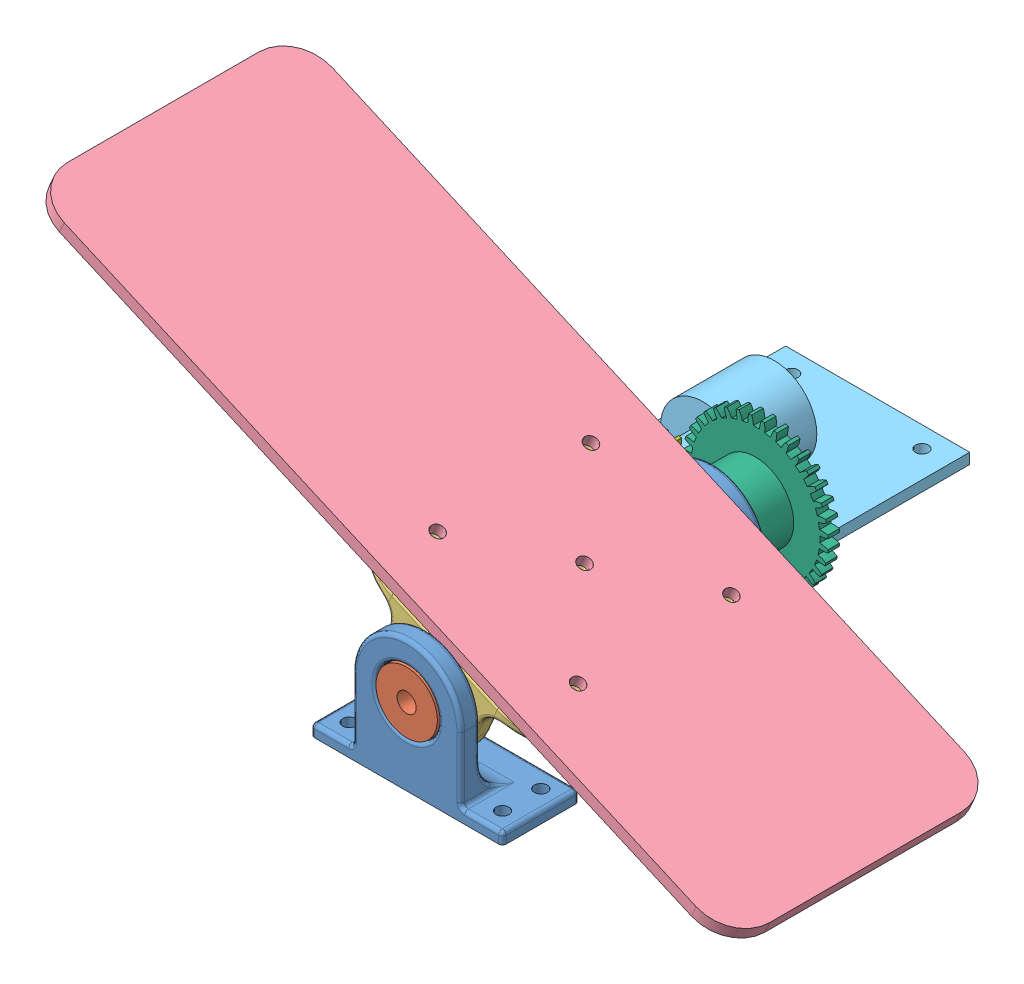
SolidWorks assembly pedalEnsable, configuration Predeterminado. Lengths in mm.
Overall size (184.44 88.48 147.22).
9 component instances, 7 part files, 17 mates.
Components (placement in the parent):
- abrazadera5-16-4: abrazadera5-16 [Predeterminado] x (-1 0 0) z (0 0 -1) size (50 34.12 20)
- rodamiento5-16-3: rodamiento5-16 [Predeterminado] at (0 0 -5) size (16 16 5)
- base pedal-2: base pedal [Predeterminado] at (0 0 35) x (0.916189 -0.400746 0) z (0 0 1) size (60 26 70)
- abrazadera5-16-5: abrazadera5-16 [Predeterminado] at (0 0 70) size (50 34.12 20)
- rodamiento5-16-4: rodamiento5-16 [Predeterminado] at (0 0 70) size (16 16 5)
- pedal-1: pedal [Predeterminado] at (-13.1141 19.9254 35) x (0 0 -1) z (0.916189 -0.400746 0) size (70 3 200)
- pot-1: pot [Predeterminado] at (-24.3072 -6.11 -45.22) x (-1 0 0) z (0 0 -1) size (48 25 66.22)
- gear36-3: gear36 [Predeterminado] at (0 0 -5) x (-0.880719 0.47364 0) z (0 0 -1) size (37.99 37.99 14)
- gear14-3: gear14 [Predeterminado] at (-24.3072 -6.11 -4) x (-0.084602 -0.996415 0) z (0 0 -1) size (15.95 15.98 15)
Mates (geometry in assembly coordinates):
- Concéntrica7: concentric anti-aligned: cylinder of abrazadera5-16-4 through (0 0 -5) axis (0 0 1) radius 8.125; cylinder of rodamiento5-16-3 through (0 0 0) axis (0 0 -1) radius 8
- Coincidente11: coincident aligned: plane of abrazadera5-16-4 through (0 0 -5) normal (0 0 -1); plane of rodamiento5-16-3 through (0 0 -5) normal (0 0 -1)
- Concéntrica8: concentric aligned: cylinder of rodamiento5-16-3 through (0 0 0) axis (0 0 -1) radius 2.5; cylinder of base pedal-2 through (0 0 70) axis (0 0 -1) radius 2.5
- Coincidente12: coincident anti-aligned: plane of abrazadera5-16-4 through (0 0 0) normal (0 0 1); plane of base pedal-2 through (0 0 0) normal (0 0 -1)
- Concéntrica9: concentric aligned: cylinder of abrazadera5-16-5 through (0 0 75) axis (0 0 -1) radius 8.125; cylinder of rodamiento5-16-4 through (0 0 75) axis (0 0 -1) radius 8
- Coincidente13: coincident aligned: plane of abrazadera5-16-5 through (0 0 75) normal (0 0 1); plane of rodamiento5-16-4 through (0 0 75) normal (0 0 1)
- Concéntrica10: concentric aligned: cylinder of base pedal-2 through (0 0 70) axis (0 0 -1) radius 2.5; cylinder of rodamiento5-16-4 through (0 0 75) axis (0 0 -1) radius 2.5
- Coincidente14: coincident anti-aligned: plane of base pedal-2 through (0 0 70) normal (0 0 1); plane of rodamiento5-16-4 through (0 0 70) normal (0 0 -1)
- Concéntrica13: concentric aligned: cylinder of base pedal-2 through (-13.1141 19.9254 55) axis (0.400746 0.916189 0) radius 1.7; cylinder of pedal-1 through (-11.9118 22.674 55) axis (0.400746 0.916189 0) radius 1.7
- Coincidente16: coincident anti-aligned: plane of base pedal-2 through (5.2097 11.9105 70) normal (0.400746 0.916189 0); plane of pedal-1 through (69.3429 -16.1418 60) normal (-0.400746 -0.916189 0)
- Concéntrica14: concentric aligned: cylinder of base pedal-2 through (23.5335 3.8955 15) axis (0.400746 0.916189 0) radius 1.7; cylinder of pedal-1 through (24.7357 6.6441 15) axis (0.400746 0.916189 0) radius 1.7
- Coincidente19: coincident aligned: plane of abrazadera5-16-4 through (0 -20 -5) normal (0 -1 0); plane of pot-1 through (-0.3072 -20 -26.22) normal (0 -1 0)
- Concéntrica15: concentric aligned: cylinder of rodamiento5-16-3 through (0 0 0) axis (0 0 -1) radius 2.5; cylinder of gear36-3 through (0 0 -5) axis (0 0 -1) radius 2.5
- Coincidente20: coincident anti-aligned: plane of rodamiento5-16-3 through (0 0 -5) normal (0 0 -1); plane of gear36-3 through (0 0 -5) normal (0 0 1)
- Concéntrica16: concentric aligned: cylinder of pot-1 through (-24.3072 -6.11 -45.22) axis (0 0 -1) radius 3.1; cylinder of gear14-3 through (-24.3072 -6.11 -4) axis (0 0 -1) radius 3.17
- Coincidente21: coincident anti-aligned: plane of pot-1 through (-24.3072 -6.11 -6) normal (0 0 1); plane of gear14-3 through (-24.3072 -6.11 -6) normal (0 0 -1)
- Coincidente22: coincident aligned: plane of gear36-3 through (0 0 -16) normal (0 0 1); plane of gear14-3 through (-24.3072 -6.11 -16) normal (0 0 1)
